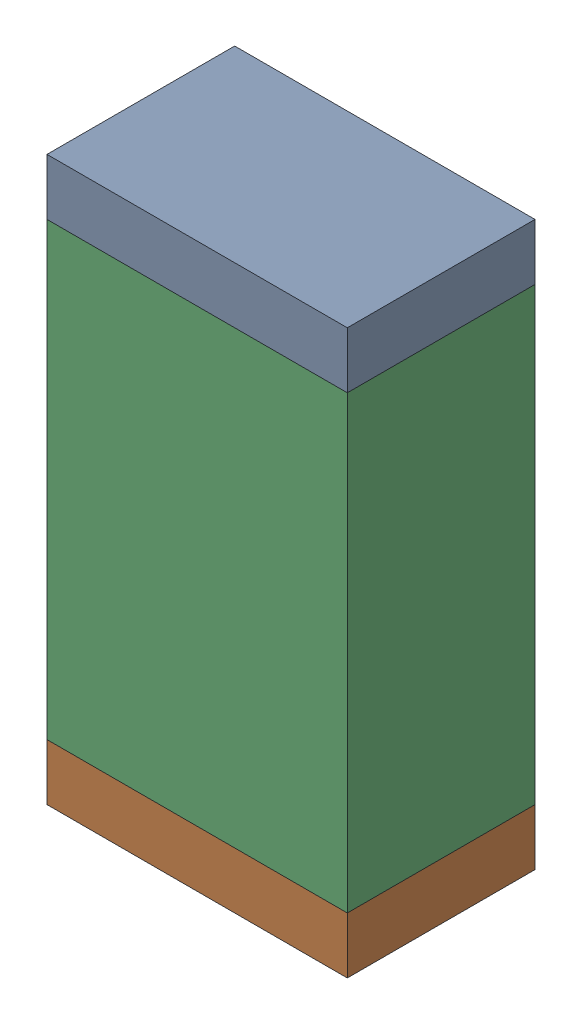
SolidWorks assembly C4, configuration Default. Lengths in mm.
Overall size (0.8 1.5 0.5).
6 component instances, 2 part files, 0 mates.
Components (placement in the parent):
- 810156592-1: 810156592 [Default] at (117.95 8.975 0) size (0.8 0.15 0.5)
  - Extruded_7-1: Extruded_7 [Default] at origin size (0.8 0.15 0.5)
- 810156592-2: 810156592 [Default] at (117.95 7.625 0) size (0.8 0.15 0.5)
  - Extruded_7-1: Extruded_7 [Default] at origin size (0.8 0.15 0.5)
- 810156976-1: 810156976 [Default] at (117.95 8.3 0) size (0.8 1.2 0.5)
  - Extruded_6-1: Extruded_6 [Default] at origin size (0.8 1.2 0.5)
